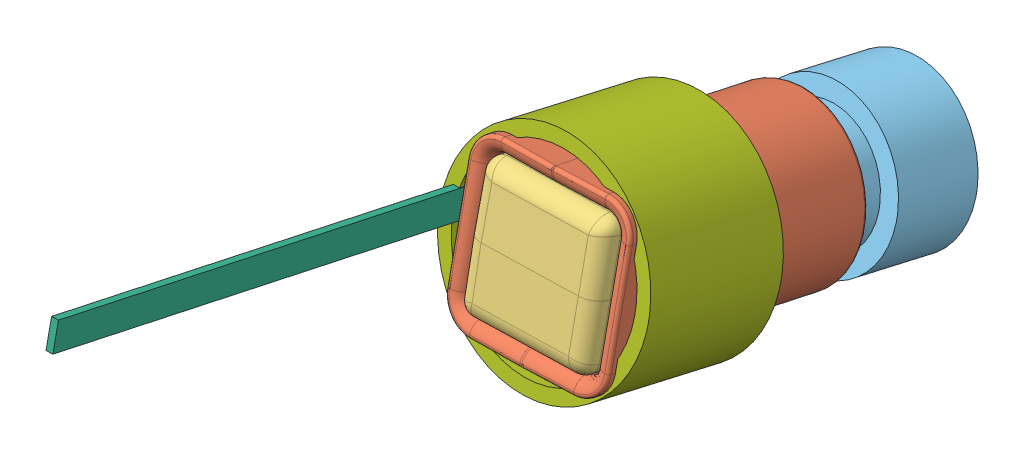
SolidWorks assembly AU-SK-2-000895, configuration Default. Lengths in mm.
Overall size (19.73 25.13 73.27).
11 component instances, 9 part files, 26 mates.
Components (placement in the parent):
- mount v5-1: mount v5 [Default] at (0 -8 0) x (-1 0 0) z (0 0 -1) (suppressed, hidden)
- holder v5-1: holder v5 [Default] at (0 -19.7357 5.909) x (-1 0 0) z (0 -0.195551 -0.980694) (suppressed, hidden)
- AU-SK-2-000864-1: AU-SK-2-000864 [Default] at (-33.5466 9.6922 -9.0615) x (0.999831 0.010415 -0.015168) z (0.013496 -0.975451 0.219803) size (10.83 7.1 10.83)
  - AU-SK-1-000863-1: AU-SK-1-000863 [Default] at (-0.3998 0.0623 0.1686) size (10.83 7.1 10.83)
- AU-SK-1-000916-1: AU-SK-1-000916 [Default] at (-33.9683 9.0973 -10.9085) x (-0.999831 -0.010415 0.015168) z (0.013496 -0.975451 0.219803) size (15.67 24.64 15.67)
- AU-SK-1-000917-1: AU-SK-1-000917 [Default] at (-33.8833 10.5931 -4.2756) x (0.013496 -0.975451 0.219803) z (0.012507 0.219971 0.975426) size (12 13 6.64)
- AU-SK-1-000919-1: AU-SK-1-000919 [Default] at (-34.0001 10.5105 -4.6349) x (0.999988 0.00055 0.004945) z (-0.004945 0.219755 0.975543) size (12.19 12.19 2.03)
- AU-SK-1-000918-2: AU-SK-1-000918 [Default] at (-33.9569 8.5923 -13.1504) x (0.999 0.044429 -0.004945) z (0.004945 -0.219755 -0.975543) size (14.25 14.25 20.32)
- AU-SK-1-000919-2: AU-SK-1-000919 [Default] at (-33.988 9.9708 -7.0312) x (0.999988 0.00055 0.004945) z (-0.004945 0.219755 0.975543) size (12.19 12.19 2.03)
- AU-SK-1-000898-1: AU-SK-1-000898 [Default] at (-36.9642 9.8499 -4.284) x (0.012507 0.219971 0.975426) z (-0.013496 0.975451 -0.219803) size (43.97 6.05 2.54)
- AU-SK-1-000920-1: AU-SK-1-000920 [Default] at (-33.9626 8.8416 -12.0435) x (0.999988 0.00055 0.004945) z (-0.004945 0.219755 0.975543) size (19.65 19.65 12.7)
Mates (geometry in assembly coordinates):
- Coincident14: coincident anti-aligned: plane of AU-SK-1-000916-1; plane of AU-SK-1-000917-1
- Coincident15: coincident aligned: plane of AU-SK-1-000916-1 through (-33.9683 9.0973 -10.9085) normal (0.013496 -0.975451 0.219803); plane of AU-SK-1-000917-1
- Coincident18: coincident anti-aligned: plane of holder v5-1 through (7.5 -19.6736 -6.5641) normal (-1 0 0); plane of AU-SK-1-000916-1
- Coincident19: coincident anti-aligned: plane of holder v5-1; plane of AU-SK-1-000916-1
- Coincident20: coincident aligned: plane of mount v5-1 through (0 -8 0) normal (-1 0 0); plane of AU-SK-1-000916-1
- Concentric10: concentric aligned: cylinder of mount v5-1 through (-1 -8 0) axis (1 0 0) radius 1.5; cylinder of holder v5-1 through (-8.775 -8 0) axis (1 0 0) radius 1.5
- Coincident21: coincident aligned: plane of mount v5-1 through (-1 0 30.8756) normal (0 1 0); plane of assembly through (0 0 0) normal (0 1 0)
- Coincident22: coincident anti-aligned: plane of mount v5-1 through (0 -8 0) normal (-1 0 0); plane of assembly through (0 0 0) normal (1 0 0)
- Coincident23: coincident anti-aligned: plane of mount v5-1 through (0 -8 0) normal (0 0 -1); plane of assembly through (0 0 0) normal (0 0 1)
- Distance3: distance = 1.8685 mm anti-aligned: plane of AU-SK-1-000916-1; plane of holder v5-1 through (3.4 -10.748 4.1169) normal (0 0.195551 0.980694)
- Coincident11: coincident aligned: plane of AU-SK-1-000916-1 through (-33.9683 9.0973 -10.9085) normal (0.013496 -0.975451 0.219803); plane of AU-SK-2-000864-1/AU-SK-1-000863-1 through (-33.9433 9.5373 -8.9576) normal (0.013496 -0.975451 0.219803)
- Coincident12: coincident anti-aligned: plane of AU-SK-1-000916-1; plane of AU-SK-2-000864-1/AU-SK-1-000863-1
- Coincident13: coincident anti-aligned: plane of AU-SK-1-000916-1 through (-26.5458 16.9313 -10.7199) normal (0.012507 0.219971 0.975426); plane of AU-SK-2-000864-1/AU-SK-1-000863-1 through (-28.6023 14.8757 -10.23) normal (-0.012507 -0.219971 -0.975426)
- Distance2: distance = 3.3 mm anti-aligned: plane of AU-SK-2-000864-1/AU-SK-1-000863-1 through (-28.5835 15.2057 -8.7668) normal (0.012507 0.219971 0.975426); line of AU-SK-1-000917-1 through (-28.2227 10.6521 -4.3614) axis (-0.999831 -0.010415 0.015168)
- Concentric11: concentric anti-aligned: circle of AU-SK-1-000916-1; circle of AU-SK-1-000919-1
- Concentric12: concentric aligned: circle of AU-SK-1-000918-2; circle of AU-SK-1-000916-1
- Distance4: distance = 3 mm anti-aligned: plane of AU-SK-1-000918-2 through (-33.8942 5.8014 -25.5398) normal (-0.004945 0.219755 0.975543); plane of AU-SK-1-000916-1 through (-35.3624 13.7573 -24.2642) normal (0.004945 -0.219755 -0.975543)
- Lock2: lock: unknown of ?; unknown of ?
- Lock3: lock: unknown of ?; unknown of ?
- Distance5: distance = 1 mm anti-aligned: plane of AU-SK-1-000916-1 through (-41.3408 2.1433 -7.1953) normal (-0.999831 -0.010415 0.015168); plane of AU-SK-1-000898-1 through (-42.3698 12.9695 -1.6632) normal (0.999831 0.010415 -0.015168)
- Distance6: distance = 0.8 mm anti-aligned: plane of AU-SK-1-000898-1 through (-36.9905 12.4672 -4.2229) normal (0.012507 0.219971 0.975426); plane of AU-SK-1-000916-1 through (-39.8385 4.9468 -1.6703) normal (-0.012507 -0.219971 -0.975426)
- Parallel1: parallel aligned: plane of AU-SK-1-000916-1 through (-26.3433 2.2995 -7.4229) normal (0.013496 -0.975451 0.219803); plane of AU-SK-1-000898-1 through (-39.796 10.5184 -1.1435) normal (0.013496 -0.975451 0.219803)
- Concentric13: concentric anti-aligned: circle of AU-SK-1-000918-2; circle of AU-SK-1-000920-1
- Parallel2: parallel aligned: plane of AU-SK-1-000916-1 through (-26.3433 2.2995 -7.4229) normal (0.013496 -0.975451 0.219803); plane of AU-SK-1-000898-1 through (-39.796 10.5184 -1.1435) normal (0.013496 -0.975451 0.219803)
- Distance7: distance = 0.9616 mm aligned: plane of AU-SK-1-000920-1 through (-34.0254 11.6325 0.3459) normal (-0.004945 0.219755 0.975543); cylinder of AU-SK-1-000916-1 through (-41.0265 5.6265 1.419) axis (0.013496 -0.975451 0.219803) radius 1.2
- Distance8: distance = 6.8184 mm aligned: plane of AU-SK-1-000898-1 through (-39.796 10.5184 -1.1435) normal (0.013496 -0.975451 0.219803); plane of AU-SK-1-000916-1 through (-26.3433 2.2995 -7.4229) normal (0.013496 -0.975451 0.219803)
